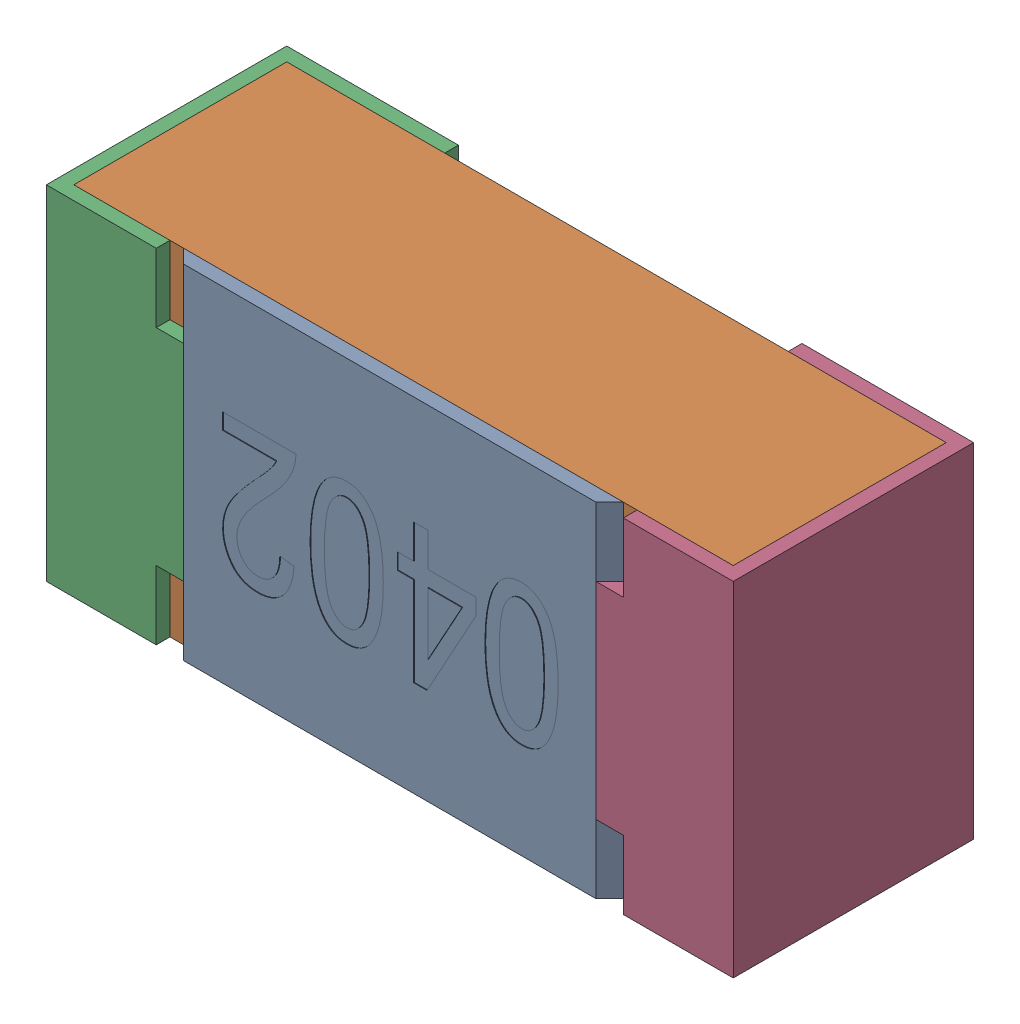
SolidWorks assembly R31, configuration Standard. Lengths in mm.
Overall size (1 0.5 0.35).
5 component instances, 4 part files, 0 mates.
Components (placement in the parent):
- R31-subassembly-1-1: R31-subassembly-1 [Standard] at (2.8999 -5.5 0) x (-1 0 0) z (0 0 1) size (1 0.5 0.35)
  - User Library-R_0402-1: User Library-R_0402 [Standard] at origin size (0.64 0.5 0.02)
  - User Library-R_0402-1-1: User Library-R_0402-1 [Standard] at origin size (0.96 0.5 0.31)
  - User Library-R_0402-2-1: User Library-R_0402-2 [Standard] at origin size (0.25 0.5 0.35)
  - User Library-R_0402-3-1: User Library-R_0402-3 [Standard] at origin size (0.25 0.5 0.35)
